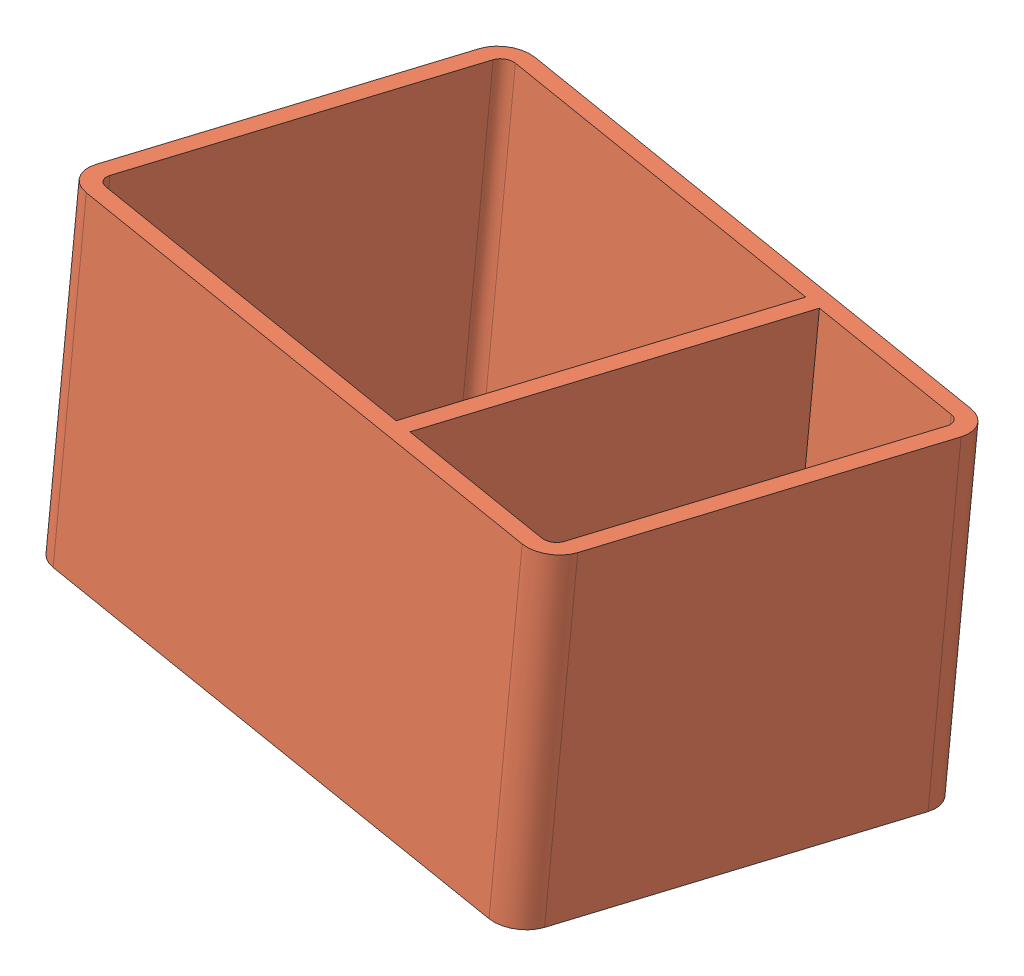
SolidWorks assembly adapter_assembly, configuration Default. Lengths in mm.
Overall size (115.62 63.04 91.17).
4 component instances, 4 part files, 5 mates.
Components (placement in the parent):
- female_pins_connector-1: female_pins_connector [Default] at (-111.8012 -2.6355 115.1126) x (-0.174038 0.101042 0.979541) z (-0.984728 -0.0131 -0.173608) size (28.3 14.72 10)
- adapter_box-1: adapter_box [Default] at (-66.2557 -4.7795 106.0899) x (0.984728 0.0131 0.173608) z (-0.174038 0.101042 0.979541) size (105 55 68.75)
- Part1^adapter_assembly-1: Part1^adapter_assembly [Default] at origin (virtual)
- terminal_chocolate_block-1: terminal_chocolate_block [Default] at (-63.6932 -3.6397 92.0256) x (0.984699 0.008883 0.174038) z (-0.174038 0.101042 0.979541) size (18.85 15 16.8) (hidden)
Mates (geometry in assembly coordinates):
- Parallel2: parallel anti-aligned: plane of female_pins_connector-1 through (-106.7324 -3.8239 103.732) normal (-0.00471 -0.994796 0.101778); plane of adapter_box-1 through (-112.6408 -3.9025 102.6903) normal (0.00471 0.994796 -0.101778)
- Parallel3: parallel anti-aligned: plane of female_pins_connector-1 through (-114.5409 10.7147 100.845) normal (-0.984728 -0.0131 -0.173608); plane of adapter_box-1 through (-119.853 52.2539 120.6725) normal (0.984728 0.0131 0.173608)
- Concentric1: concentric anti-aligned: circle of female_pins_connector-1; circle of adapter_box-1
- Coincident5: coincident aligned: line of female_pins_connector-1 through (-114.6103 -3.9287 102.3431) axis (-0.174038 0.101042 0.979541); line of adapter_box-1 through (-114.6103 -3.9287 102.3431) axis (-0.174038 0.101042 0.979541)
- Parallel4: parallel anti-aligned: plane of adapter_box-1 through (-13.7616 47.3863 78.0053) normal (-0.174038 0.101042 0.979541); plane of terminal_chocolate_block-1 through (-61.0194 2.8079 76.5683) normal (0.174038 -0.101042 -0.979541)
